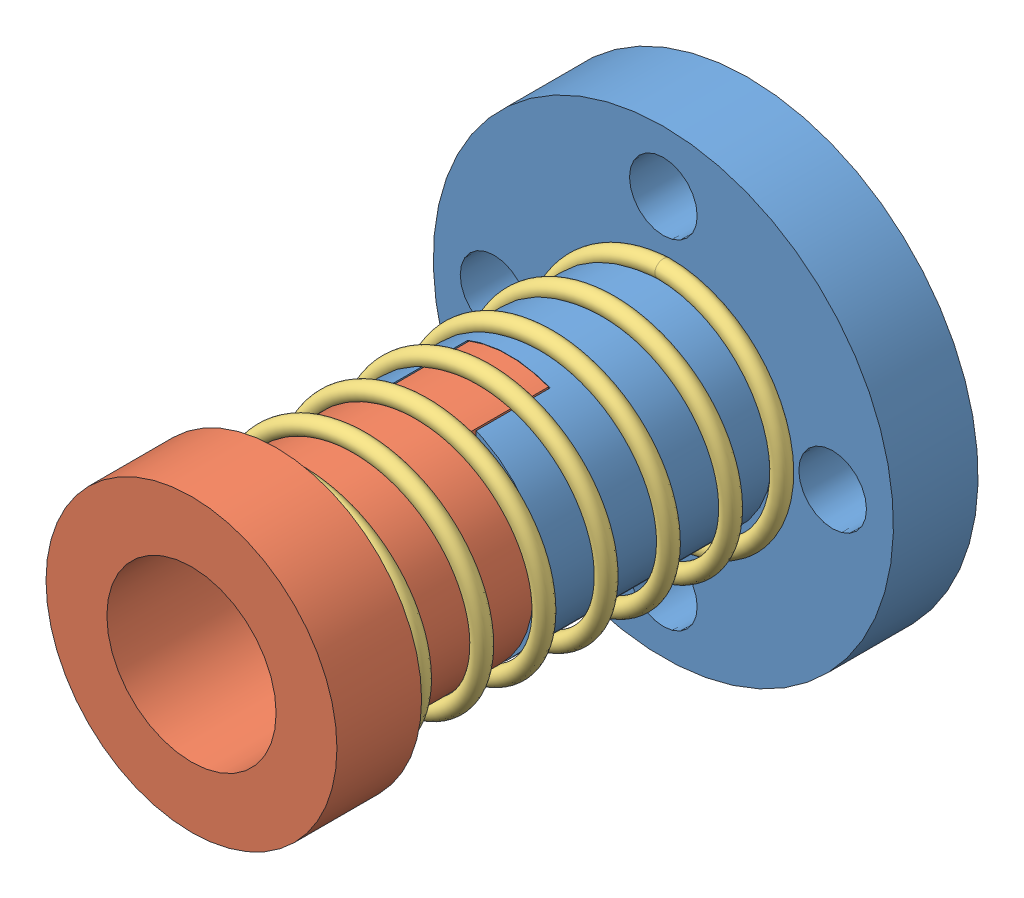
SolidWorks assembly TR08, configuration Predeterminado. Lengths in mm.
Overall size (21.75 21.75 26.3).
3 component instances, 3 part files, 4 mates.
Components (placement in the parent):
- nakretka tr08-1: nakretka tr08 [Predeterminado] at (20.7471 35.4278 19.4357) x (1 0 0) z (0 1 0) size (21.75 14.8 21.75)
- napinacz nakretki tr8-1: napinacz nakretki tr8 [Predeterminado] at (20.7471 35.4278 41.7357) x (-1 0 0) z (0 -1 0) size (13.75 15 13.75)
- sprezyna nakretka tr 8-1: sprezyna nakretka tr 8 [Predeterminado] at (21.1556 35.3914 19.8355) x (0.999661 0 0.026047) z (-0.026047 0 0.999661) size (12.35 12.39 19.87)
Mates (geometry in assembly coordinates):
- Tangente1: tangent anti-aligned: plane of nakretka tr08-1 through (20.7471 35.4278 19.4357) normal (0 0 1); face of sprezyna nakretka tr 8-1
- Coincidente1: coincident anti-aligned: plane of nakretka tr08-1 through (20.7471 30.2578 26.7357) normal (0 0 1); plane of napinacz nakretki tr8-1 through (20.7471 35.4278 26.7357) normal (0 0 -1)
- Concéntrica1: concentric anti-aligned: cylinder of nakretka tr08-1 through (20.7471 35.4278 19.4357) axis (0 0 1) radius 5.17; cylinder of napinacz nakretki tr8-1 through (20.7471 35.4278 37.7357) axis (0 0 -1) radius 5.15
- Tangente3: tangent anti-aligned: cylinder of nakretka tr08-1 through (20.7471 35.4278 19.4357) axis (0 0 1) radius 5.17; edge_curve of sprezyna nakretka tr 8-1
